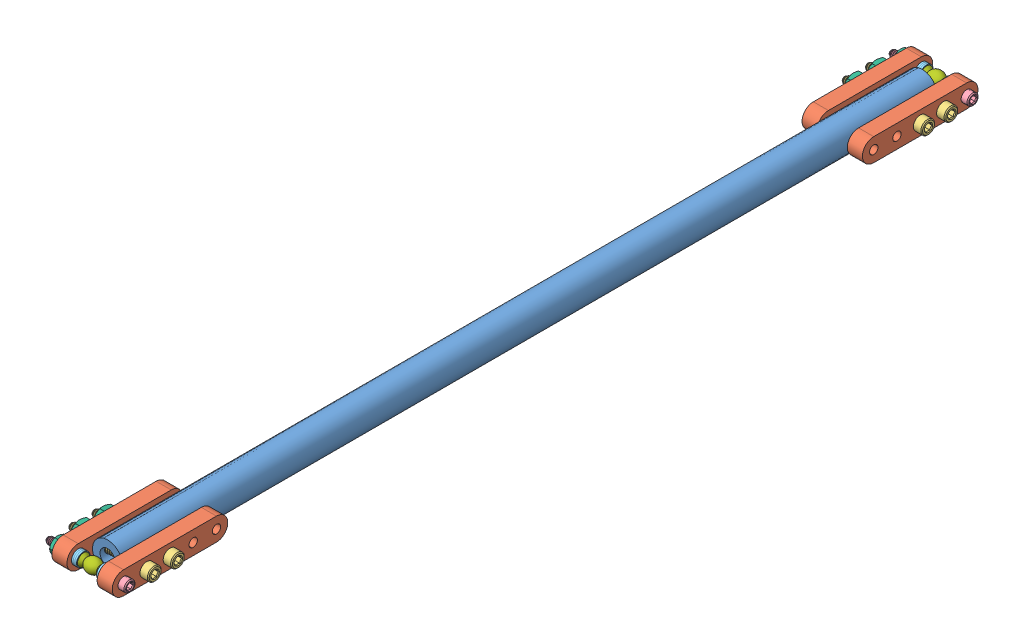
SolidWorks assembly Diff Pivot Top, configuration Default. Lengths in mm.
Overall size (35.29 12.7 364.36).
31 component instances, 7 part files, 34 mates.
Components (placement in the parent):
- 13.5 Inch Aluminum Rod-1: 13.5 Inch Aluminum Rod [Default] at (112.518 164.0173 110.0632) size (12.7 12.7 342.9)
- 5 Hole Aluminum Beam-1: 5 Hole Aluminum Beam [Default] at (106.168 164.0173 439.3742) x (0 0 -1) z (0 1 0) size (48.64 6.35 9.53)
- 5 Hole Aluminum Beam-2: 5 Hole Aluminum Beam [Default] at (125.218 164.0173 439.3742) x (0 0 -1) z (0 1 0) size (48.64 6.35 9.53)
- 6-32_SHCS-1: 6-32_SHCS [6-32 SHCS X 1.250] at (93.468 164.0173 449.1532) x (0 0 -1) z (1 0 0) size (5.74 5.74 35.26)
- 6-32_SHCS-2: 6-32_SHCS [6-32 SHCS X 1.250] at (93.468 164.0173 439.3742) x (0 0 -1) z (1 0 0) size (5.74 5.74 35.26)
- 4-40_SHCS-1: 4-40_SHCS [4-40 SHCS X 1.250] at (93.468 164.0173 458.9322) x (0 -0.924225 -0.381849) z (1 0 0) size (4.65 4.65 34.63)
- 4-40 Washer-1: 4-40 Washer [Default] at (118.1568 164.0173 458.9322) x (0 -1 0) z (0 0 1) size (5.71 0.71 5.71)
- 4-40 Washer-2: 4-40 Washer [Default] at (118.1568 164.0173 458.9322) x (0 1 0) z (0 0 1) size (5.71 0.71 5.71)
- 4-40 Washer-3: 4-40 Washer [Default] at (116.7344 164.0173 458.9322) x (0 -1 0) z (0 0 1) size (5.71 0.71 5.71)
- 4-40 Washer-4: 4-40 Washer [Default] at (106.168 164.0173 458.9322) x (0 -1 0) z (0 0 1) size (5.71 0.71 5.71)
- 4-40 Washer-5: 4-40 Washer [Default] at (107.5904 164.0173 458.9322) x (0 -1 0) z (0 0 1) size (5.71 0.71 5.71)
- 4-40 Washer-6: 4-40 Washer [Default] at (106.8792 164.0173 458.9322) x (0 -1 0) z (0 0 1) size (5.71 0.71 5.71)
- hex_nut-1: hex_nut [#6-32] at (99.818 164.0173 449.1532) x (0 1 0) z (0 0 1) size (7.92 2.9 10.06)
- hex_nut-2: hex_nut [#6-32] at (99.818 164.0173 439.3742) x (0 0.381849 -0.924225) z (0 0.924225 0.381849) size (7.92 2.9 10.06)
- hex_nut-3: hex_nut [#4-40] at (99.818 164.0173 458.9322) x (0 -0.381849 0.924225) z (0 -0.924225 -0.381849) size (6.35 2.49 8.06)
- 5 Hole Aluminum Beam-3: 5 Hole Aluminum Beam [Default] at (99.818 164.0173 123.6522) x (0 0 1) z (0 1 0) size (48.64 6.35 9.53)
- 5 Hole Aluminum Beam-4: 5 Hole Aluminum Beam [Default] at (118.868 164.0173 123.6522) x (0 0 1) z (0 1 0) size (48.64 6.35 9.53)
- 6-32_SHCS-3: 6-32_SHCS [6-32 SHCS X 1.250] at (93.468 164.0173 113.8732) x (0 0 -1) z (1 0 0) size (5.74 5.74 35.26)
- 6-32_SHCS-4: 6-32_SHCS [6-32 SHCS X 1.250] at (93.468 164.0173 123.6522) x (0 0 -1) z (1 0 0) size (5.74 5.74 35.26)
- 4-40_SHCS-2: 4-40_SHCS [4-40 SHCS X 1.250] at (93.468 164.0173 104.0942) x (0 0.924225 -0.381849) z (1 0 0) size (4.65 4.65 34.63)
- 4-40 Washer-7: 4-40 Washer [Default] at (118.1568 164.0173 104.0942) x (0 -1 0) z (0 0 1) size (5.71 0.71 5.71)
- 4-40 Washer-8: 4-40 Washer [Default] at (118.1568 164.0173 104.0942) x (0 1 0) z (0 0 1) size (5.71 0.71 5.71)
- 4-40 Washer-9: 4-40 Washer [Default] at (116.7344 164.0173 104.0942) x (0 -1 0) z (0 0 1) size (5.71 0.71 5.71)
- 4-40 Washer-10: 4-40 Washer [Default] at (106.168 164.0173 104.0942) x (0 -1 0) z (0 0 1) size (5.71 0.71 5.71)
- 4-40 Washer-11: 4-40 Washer [Default] at (107.5904 164.0173 104.0942) x (0 -1 0) z (0 0 1) size (5.71 0.71 5.71)
- 4-40 Washer-12: 4-40 Washer [Default] at (106.8792 164.0173 104.0942) x (0 -1 0) z (0 0 1) size (5.71 0.71 5.71)
- hex_nut-4: hex_nut [#6-32] at (99.818 164.0173 113.8732) x (0 1 0) z (0 0 1) size (7.92 2.9 10.06)
- hex_nut-5: hex_nut [#4-40] at (99.818 164.0173 104.0942) x (0 -0.381849 -0.924225) z (0 0.924225 -0.381849) size (6.35 2.49 8.06)
- hex_nut-6: hex_nut [#6-32] at (99.818 164.0173 123.6522) x (0 0.381849 0.924225) z (0 -0.924225 0.381849) size (7.92 2.9 10.06)
- Ball bearing-1: Ball bearing [Default] at (116.6455 164.0173 458.9322) x (0 1 0) z (0 0 1) size (5.73 8.26 5.73)
- Ball bearing-2: Ball bearing [Default] at (108.3905 164.0173 104.0942) x (0 -1 0) z (0 0 1) size (5.73 8.26 5.73)
Mates (geometry in assembly coordinates):
- Concentric3: concentric anti-aligned: cylinder of 13.5 Inch Aluminum Rod-1 through (-65.282 164.0173 439.3742) axis (1 0 0) radius 1.905; cylinder of 5 Hole Aluminum Beam-2 through (118.868 164.0173 439.3742) axis (-1 0 0) radius 1.778
- Concentric4: concentric anti-aligned: cylinder of 13.5 Inch Aluminum Rod-1 through (-65.282 164.0173 439.3742) axis (1 0 0) radius 1.905; cylinder of 5 Hole Aluminum Beam-1 through (99.818 164.0173 439.3742) axis (-1 0 0) radius 1.778
- Concentric5: concentric anti-aligned: cylinder of 13.5 Inch Aluminum Rod-1 through (-65.282 164.0173 439.3742) axis (1 0 0) radius 1.905; cylinder of 6-32_SHCS-2 through (137.918 164.0173 439.3742) axis (-1 0 0) radius 2.8702
- Concentric6: concentric aligned: cylinder of 5 Hole Aluminum Beam-1 through (99.818 164.0173 439.3742) axis (-1 0 0) radius 1.778; cylinder of hex_nut-2 through (98.1544 164.0173 439.3742) axis (-1 0 0) radius 1.323
- Concentric7: concentric anti-aligned: cylinder of 13.5 Inch Aluminum Rod-1 through (-65.282 164.0173 449.1532) axis (1 0 0) radius 1.905; cylinder of 5 Hole Aluminum Beam-1 through (99.818 164.0173 449.1532) axis (-1 0 0) radius 1.778
- Concentric8: concentric anti-aligned: cylinder of 13.5 Inch Aluminum Rod-1 through (-65.282 164.0173 449.1532) axis (1 0 0) radius 1.905; cylinder of 5 Hole Aluminum Beam-2 through (118.868 164.0173 449.1532) axis (-1 0 0) radius 1.778
- Concentric9: concentric anti-aligned: cylinder of 13.5 Inch Aluminum Rod-1 through (-65.282 164.0173 449.1532) axis (1 0 0) radius 1.905; cylinder of 6-32_SHCS-1 through (137.918 164.0173 449.1532) axis (-1 0 0) radius 2.8702
- Concentric10: concentric aligned: cylinder of 13.5 Inch Aluminum Rod-1 through (-65.282 164.0173 449.1532) axis (1 0 0) radius 1.905; cone of hex_nut-1 through (97.5177 164.0173 449.1532) axis (1 0 0)
- Tangent1: tangent anti-aligned: cylinder of 13.5 Inch Aluminum Rod-1 through (112.518 164.0173 452.9632) axis (0 0 -1) radius 6.35; plane of 5 Hole Aluminum Beam-1 through (106.168 164.0173 458.9322) normal (1 0 0)
- Tangent3: tangent anti-aligned: cylinder of 13.5 Inch Aluminum Rod-1 through (112.518 164.0173 452.9632) axis (0 0 -1) radius 6.35; plane of 5 Hole Aluminum Beam-2 through (118.868 164.0173 458.9322) normal (-1 0 0)
- Coincident1: coincident aligned: plane of 6-32_SHCS-2 through (125.218 164.0173 439.3742) normal (-1 0 0); plane of 6-32_SHCS-1 through (125.218 164.0173 449.1532) normal (-1 0 0)
- Coincident2: coincident anti-aligned: plane of 6-32_SHCS-2 through (125.218 164.0173 439.3742) normal (-1 0 0); plane of 5 Hole Aluminum Beam-2 through (125.218 164.0173 458.9322) normal (1 0 0)
- Coincident3: coincident anti-aligned: plane of 5 Hole Aluminum Beam-1 through (99.818 164.0173 458.9322) normal (-1 0 0); plane of hex_nut-2 through (99.818 156.1613 440.4157) normal (1 0 0)
- Coincident4: coincident anti-aligned: plane of 5 Hole Aluminum Beam-1 through (99.818 164.0173 458.9322) normal (-1 0 0); plane of hex_nut-1 through (99.818 160.0549 442.2902) normal (1 0 0)
- Concentric12: concentric aligned: cylinder of 5 Hole Aluminum Beam-2 through (118.868 164.0173 458.9322) axis (-1 0 0) radius 1.778; cylinder of 4-40 Washer-2 through (117.4456 164.0173 458.9322) axis (-1 0 0) radius 1.4732
- Concentric13: concentric anti-aligned: cylinder of 5 Hole Aluminum Beam-2 through (118.868 164.0173 458.9322) axis (-1 0 0) radius 1.778; cylinder of 4-40 Washer-6 through (107.5904 164.0173 458.9322) axis (1 0 0) radius 1.4732
- Concentric14: concentric anti-aligned: cylinder of 5 Hole Aluminum Beam-2 through (118.868 164.0173 458.9322) axis (-1 0 0) radius 1.778; cylinder of 4-40 Washer-4 through (106.8792 164.0173 458.9322) axis (1 0 0) radius 1.4732
- Concentric15: concentric anti-aligned: cylinder of 5 Hole Aluminum Beam-2 through (118.868 164.0173 458.9322) axis (-1 0 0) radius 1.778; cylinder of 4-40 Washer-5 through (108.3016 164.0173 458.9322) axis (1 0 0) radius 1.4732
- Concentric16: concentric anti-aligned: cylinder of 5 Hole Aluminum Beam-2 through (118.868 164.0173 458.9322) axis (-1 0 0) radius 1.778; cylinder of 4-40 Washer-3 through (117.4456 164.0173 458.9322) axis (1 0 0) radius 1.4732
- Concentric17: concentric anti-aligned: cylinder of 5 Hole Aluminum Beam-2 through (118.868 164.0173 458.9322) axis (-1 0 0) radius 1.778; cylinder of 4-40 Washer-1 through (118.868 164.0173 458.9322) axis (1 0 0) radius 1.4732
- Concentric19: concentric aligned: cylinder of 5 Hole Aluminum Beam-2 through (118.868 164.0173 458.9322) axis (-1 0 0) radius 1.778; cylinder of hex_nut-3 through (98.1544 164.0173 458.9322) axis (-1 0 0) radius 1.0787
- Coincident5: coincident anti-aligned: plane of 5 Hole Aluminum Beam-2 through (125.218 164.0173 458.9322) normal (1 0 0); plane of 4-40_SHCS-1 through (125.218 164.0173 458.9322) normal (-1 0 0)
- Coincident6: coincident anti-aligned: plane of 5 Hole Aluminum Beam-1 through (99.818 164.0173 458.9322) normal (-1 0 0); plane of hex_nut-3 through (99.818 167.4057 460.3322) normal (1 0 0)
- Coincident7: coincident anti-aligned: plane of 4-40 Washer-4 through (106.8792 164.0173 458.9322) normal (1 0 0); plane of 4-40 Washer-6 through (106.8792 164.0173 458.9322) normal (-1 0 0)
- Coincident8: coincident aligned: circle of 4-40 Washer-5; plane of 4-40 Washer-6 through (107.5904 164.0173 458.9322) normal (1 0 0)
- Coincident9: coincident anti-aligned: plane of 4-40 Washer-1 through (118.1568 164.0173 458.9322) normal (-1 0 0); plane of 4-40 Washer-2 through (118.1568 164.0173 458.9322) normal (1 0 0)
- Coincident10: coincident anti-aligned: plane of 4-40 Washer-2 through (117.4456 164.0173 458.9322) normal (-1 0 0); plane of 4-40 Washer-3 through (117.4456 164.0173 458.9322) normal (1 0 0)
- Coincident11: coincident anti-aligned: plane of 5 Hole Aluminum Beam-2 through (118.868 164.0173 458.9322) normal (-1 0 0); plane of 4-40 Washer-1 through (118.868 164.0173 458.9322) normal (1 0 0)
- Coincident12: coincident anti-aligned: plane of 5 Hole Aluminum Beam-1 through (106.168 164.0173 458.9322) normal (1 0 0); plane of 4-40 Washer-4 through (106.168 164.0173 458.9322) normal (-1 0 0)
- Concentric20: concentric anti-aligned: circle of 5 Hole Aluminum Beam-2; cylinder of 4-40_SHCS-1 through (137.918 164.0173 458.9322) axis (-1 0 0) radius 2.3241
- Coincident13: coincident anti-aligned: plane of Ball bearing-1 through (112.518 164.0173 458.9322) normal (-1 0 0)
- Coincident14: coincident anti-aligned: plane of Ball bearing-1 through (112.518 164.0173 458.9322) normal (-1 0 0); plane of Ball bearing-2 through (112.518 164.0173 104.0942) normal (1 0 0)
- Concentric21: concentric anti-aligned: cylinder of 4-40_SHCS-2 through (137.918 164.0173 104.0942) axis (-1 0 0) radius 2.3241; cylinder of Ball bearing-2 through (116.3915 164.0173 104.0942) axis (1 0 0) radius 1.016
- Concentric22: concentric aligned: cylinder of 4-40_SHCS-1 through (137.918 164.0173 458.9322) axis (-1 0 0) radius 2.3241; cylinder of Ball bearing-1 through (108.6445 164.0173 458.9322) axis (-1 0 0) radius 1.016
